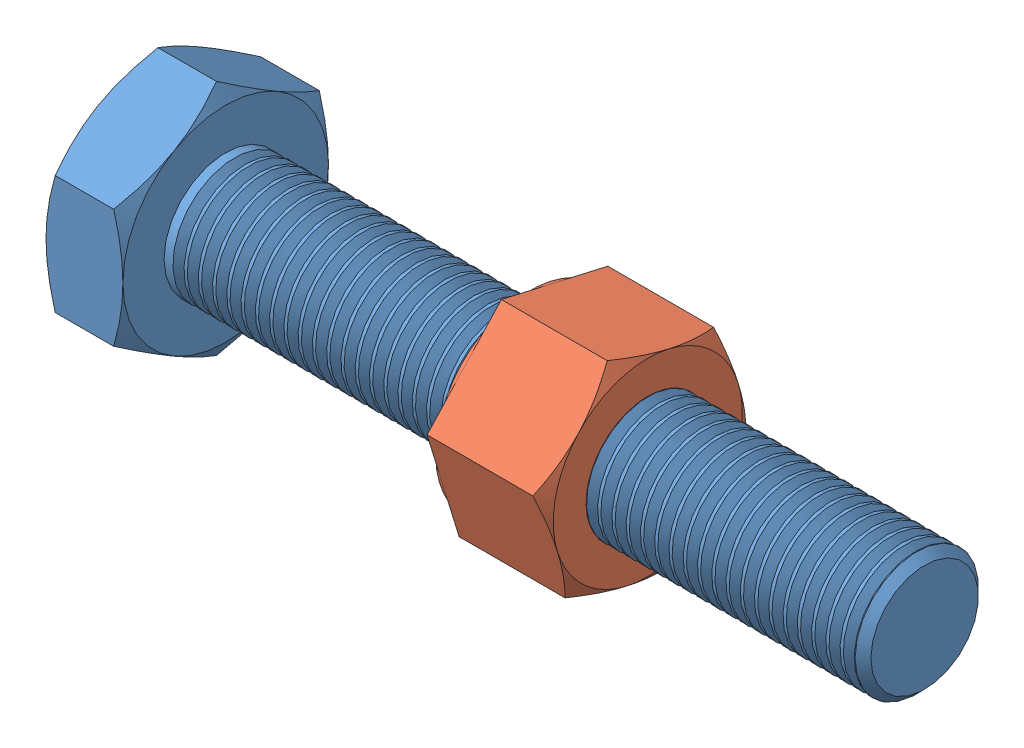
SolidWorks assembly Assem1, configuration Default. Lengths in mm.
Overall size (188.7 70.22 69.85).
2 component instances, 2 part files, 2 mates.
Components (placement in the parent):
- hex structural bolt gradec short_iso-1: hex structural bolt gradec short_iso [ISO 7412 - M30 x 170 --- 170-CS] at (-103.9391 9.8524 4.6196) size (188.7 57.74 50)
- hex nut style 2 gradeab_iso-1: hex nut style 2 gradeab_iso [ISO - 4033 - M30 - W - S] at (17.4271 9.8524 4.6196) x (0 0.680583 0.732671) z (1 0 0) size (46 53.12 28.6)
Mates (geometry in assembly coordinates):
- Concentric1: concentric anti-aligned: cylinder of hex structural bolt gradec short_iso-1 through (-103.9391 9.8524 4.6196) axis (-1 0 0) radius 15; cylinder of hex nut style 2 gradeab_iso-1 through (-11.1729 9.8524 4.6196) axis (1 0 0) radius 13.25
- Screw1: screw = 10 mm anti-aligned: cylinder of hex structural bolt gradec short_iso-1 through (-103.9391 9.8524 4.6196) axis (-1 0 0) radius 15; cylinder of hex nut style 2 gradeab_iso-1 through (-11.1729 9.8524 4.6196) axis (1 0 0) radius 13.25
